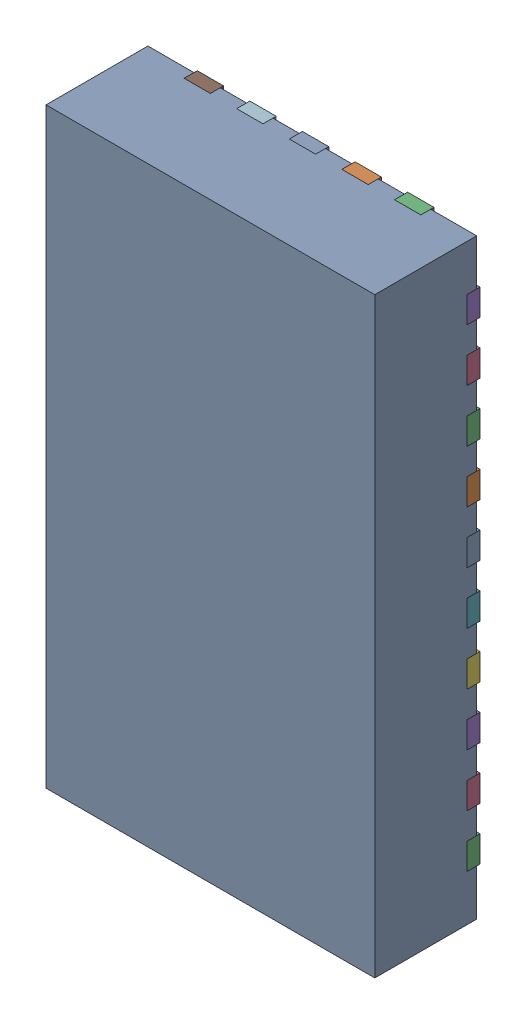
SolidWorks assembly U1, configuration Défaut. Lengths in mm.
Overall size (2.5 4.5 0.8).
36 component instances, 33 part files, 0 mates.
Components (placement in the parent):
- RNH0030A-1: RNH0030A [Défaut] at (58.0198 -20.0184 0) x (1 0 0) z (0 0 1) size (2.5 4.5 0.8)
  - BODY-QFN-1: BODY-QFN [Défaut] at (0 0 0.025) x (1 0 0) z (0 -1 0) size (2.5 0.78 4.5)
  - FRAME-RNH0030A-1: FRAME-RNH0030A [Défaut] x (1 0 0) z (0 -1 0) size (2.5 0.2 4.5)
    - Open CASCADE STEP translator 7.5 2.204.1.2.1-1: Open CASCADE STEP translator 7.5 2.204.1.2.1 [Défaut] at origin size (1.4 0.2 3.4)
    - Open CASCADE STEP translator 7.5 2.204.1.2.2-1: Open CASCADE STEP translator 7.5 2.204.1.2.2 [Défaut] at origin size (0.3 0.1 0.2)
    - Open CASCADE STEP translator 7.5 2.204.1.2.3-1: Open CASCADE STEP translator 7.5 2.204.1.2.3 [Défaut] at origin size (0.3 0.1 0.2)
    - Open CASCADE STEP translator 7.5 2.204.1.2.4-1: Open CASCADE STEP translator 7.5 2.204.1.2.4 [Défaut] at origin size (0.3 0.1 0.2)
    - Open CASCADE STEP translator 7.5 2.204.1.2.5-1: Open CASCADE STEP translator 7.5 2.204.1.2.5 [Défaut] at origin size (0.3 0.1 0.2)
    - Open CASCADE STEP translator 7.5 2.204.1.2.6-1: Open CASCADE STEP translator 7.5 2.204.1.2.6 [Défaut] at origin size (0.3 0.1 0.2)
    - Open CASCADE STEP translator 7.5 2.204.1.2.7-1: Open CASCADE STEP translator 7.5 2.204.1.2.7 [Défaut] at origin size (0.3 0.1 0.2)
    - Open CASCADE STEP translator 7.5 2.204.1.2.8-1: Open CASCADE STEP translator 7.5 2.204.1.2.8 [Défaut] at origin size (0.3 0.1 0.2)
    - Open CASCADE STEP translator 7.5 2.204.1.2.9-1: Open CASCADE STEP translator 7.5 2.204.1.2.9 [Défaut] at origin size (0.3 0.1 0.2)
    - Open CASCADE STEP translator 7.5 2.204.1.2.10-1: Open CASCADE STEP translator 7.5 2.204.1.2.10 [Défaut] at origin size (0.3 0.1 0.2)
    - Open CASCADE STEP translator 7.5 2.204.1.2.11-1: Open CASCADE STEP translator 7.5 2.204.1.2.11 [Défaut] at origin size (0.3 0.1 0.2)
    - Open CASCADE STEP translator 7.5 2.204.1.2.12-1: Open CASCADE STEP translator 7.5 2.204.1.2.12 [Défaut] at origin size (0.3 0.1 0.2)
    - Open CASCADE STEP translator 7.5 2.204.1.2.13-1: Open CASCADE STEP translator 7.5 2.204.1.2.13 [Défaut] at origin size (0.3 0.1 0.2)
    - Open CASCADE STEP translator 7.5 2.204.1.2.14-1: Open CASCADE STEP translator 7.5 2.204.1.2.14 [Défaut] at origin size (0.3 0.1 0.2)
    - Open CASCADE STEP translator 7.5 2.204.1.2.15-1: Open CASCADE STEP translator 7.5 2.204.1.2.15 [Défaut] at origin size (0.3 0.1 0.2)
    - Open CASCADE STEP translator 7.5 2.204.1.2.16-1: Open CASCADE STEP translator 7.5 2.204.1.2.16 [Défaut] at origin size (0.3 0.1 0.2)
    - Open CASCADE STEP translator 7.5 2.204.1.2.17-1: Open CASCADE STEP translator 7.5 2.204.1.2.17 [Défaut] at origin size (0.3 0.1 0.2)
    - Open CASCADE STEP translator 7.5 2.204.1.2.18-1: Open CASCADE STEP translator 7.5 2.204.1.2.18 [Défaut] at origin size (0.3 0.1 0.2)
    - Open CASCADE STEP translator 7.5 2.204.1.2.19-1: Open CASCADE STEP translator 7.5 2.204.1.2.19 [Défaut] at origin size (0.3 0.1 0.2)
    - Open CASCADE STEP translator 7.5 2.204.1.2.20-1: Open CASCADE STEP translator 7.5 2.204.1.2.20 [Défaut] at origin size (0.3 0.1 0.2)
    - Open CASCADE STEP translator 7.5 2.204.1.2.21-1: Open CASCADE STEP translator 7.5 2.204.1.2.21 [Défaut] at origin size (0.3 0.1 0.2)
    - Open CASCADE STEP translator 7.5 2.204.1.2.22-1: Open CASCADE STEP translator 7.5 2.204.1.2.22 [Défaut] at origin size (0.2 0.1 0.3)
    - Open CASCADE STEP translator 7.5 2.204.1.2.23-1: Open CASCADE STEP translator 7.5 2.204.1.2.23 [Défaut] at origin size (0.2 0.1 0.3)
    - Open CASCADE STEP translator 7.5 2.204.1.2.24-1: Open CASCADE STEP translator 7.5 2.204.1.2.24 [Défaut] at origin size (0.2 0.1 0.3)
    - Open CASCADE STEP translator 7.5 2.204.1.2.25-1: Open CASCADE STEP translator 7.5 2.204.1.2.25 [Défaut] at origin size (0.2 0.1 0.3)
    - Open CASCADE STEP translator 7.5 2.204.1.2.26-1: Open CASCADE STEP translator 7.5 2.204.1.2.26 [Défaut] at origin size (0.2 0.1 0.3)
    - Open CASCADE STEP translator 7.5 2.204.1.2.27-1: Open CASCADE STEP translator 7.5 2.204.1.2.27 [Défaut] at origin size (0.2 0.1 0.3)
    - Open CASCADE STEP translator 7.5 2.204.1.2.28-1: Open CASCADE STEP translator 7.5 2.204.1.2.28 [Défaut] at origin size (0.2 0.1 0.3)
    - Open CASCADE STEP translator 7.5 2.204.1.2.29-1: Open CASCADE STEP translator 7.5 2.204.1.2.29 [Défaut] at origin size (0.2 0.1 0.3)
    - Open CASCADE STEP translator 7.5 2.204.1.2.30-1: Open CASCADE STEP translator 7.5 2.204.1.2.30 [Défaut] at origin size (0.2 0.1 0.3)
    - Open CASCADE STEP translator 7.5 2.204.1.2.31-1: Open CASCADE STEP translator 7.5 2.204.1.2.31 [Défaut] at origin size (0.2 0.1 0.3)
- 8260085744-1: 8260085744 [Défaut] at (58.1468 -19.8914 0) size (0.25 0.25 0.25)
  - Extruded_982-1: Extruded_982 [Défaut] at origin size (0.25 0.25 0.25)
